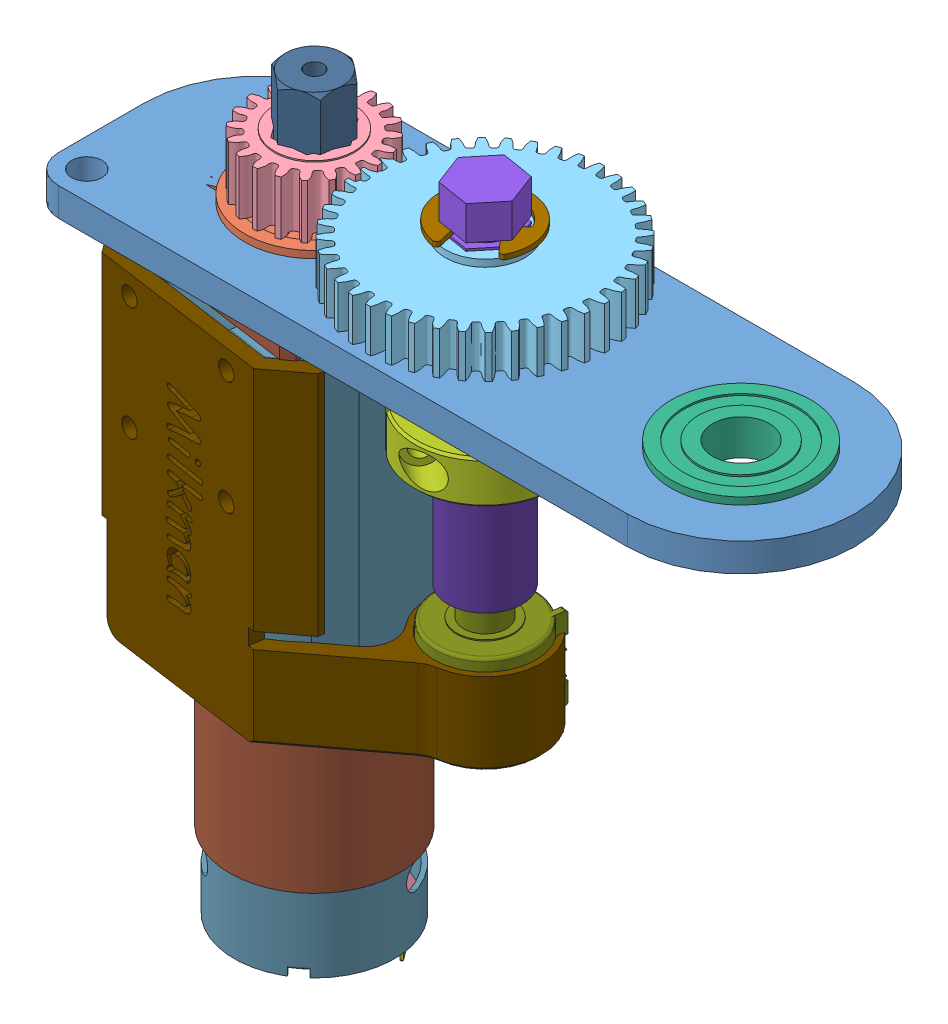
SolidWorks assembly 2018-311-A, configuration Default. Lengths in mm.
Overall size (159.56 178.63 76.64).
108 component instances, 61 part files, 41 mates.
Components (placement in the parent):
- 2018-311-D001-1: 2018-311-D001 [Default] at origin size (158.75 6.35 50.8)
- 2018-311-D003-1: 2018-311-D003 [Default] x (-0.99522 0 0.097661) z (-0.097661 0 -0.99522) size (31.12 7.94 31.12)
- 2018-311-D003-2: 2018-311-D003 [Default] at (38.1 0 0) x (-0.633642 0 0.773626) z (-0.773626 0 -0.633642) size (31.12 7.94 31.12)
- 72t_Aluminum_Spur_Gear_20_DP_1_2_Hex_Bore_VersaKeys_217-2716-1: 72t_Aluminum_Spur_Gear_20_DP_1_2_Hex_Bore_VersaKeys_217-2716 [Default] at (-78.0982 127.7889 163.8783) x (-0.237785 0 -0.971318) z (0 1 0) size (94.86 94.86 12.65) (hidden)
- VersaPlanetary-100-1-BAG-1: VersaPlanetary-100-1-BAG [Default] at (0 -16.625 -22.225) x (0 1 0) z (1 0 0) size (176.1 63.56 63.56) (hidden, flexible)
  - 217-2625-026 Rev1-1: 217-2625-026 Rev1 [Default] at (-6.5 22.225 0) x (0 -1 0) z (-1 0 0) size (44.45 42 18.13)
  - 217-2742-001 Rev4-1: 217-2742-001 Rev4 [Default] at (0.2002 22.225 0) x (1 0 0) z (0 -0.092627 0.995701) size (7 28 28)
  - 217-2742-001 Rev4-2: 217-2742-001 Rev4 [Default] at (8.2002 22.225 0) size (7 28 28)
  - 217-2625-017 Rev1_9714K61-1: 217-2625-017 Rev1_9714K61 [Default] at (7.42 22.3002 -0.342) x (0 0.56703 0.823697) z (0 -0.823697 0.56703) size (28.51 4.98 30.18)
  - 217-2625-003 Rev1-1: 217-2625-003 Rev1 [Default] at (7.4478 22.225 0) x (0 -0.99522 -0.097661) z (1 0 0) size (17 17 64.12)
  - 217-2625-018 Rev1_98541A410-1: 217-2625-018 Rev1_98541A410 [Default] at (-0.7046 22.225 0) x (1 0 0) z (0 -0.017452 0.999848) size (1 19.6 17.4)
  - 832-2250-Base-Kit-Screw_SSA0832-0500ZC-1: 832-2250-Base-Kit-Screw_SSA0832-0500ZC [Default] at (-43.4 4.725 -17.5) x (0 -0.767799 -0.640691) z (0 0.640691 -0.767799) size (6.73 61.21 6.73)
  - 832-2250-Base-Kit-Screw_SSA0832-0500ZC-2: 832-2250-Base-Kit-Screw_SSA0832-0500ZC [Default] at (-43.4 39.725 17.5) x (0 0.961307 0.275478) z (0 -0.275478 0.961307) size (6.73 61.21 6.73)
  - 217-2625-025 Rev1-1: 217-2625-025 Rev1 [Default] at (-35.9 22.225 0) x (0 -1 0) z (-1 0 0) size (44.45 42 18)
  - 217-4649-002 Rev1_SSA0832-0500ZC-1: 217-4649-002 Rev1_SSA0832-0500ZC [Default] at (-46.4 4.2645 17.9605) x (0 0.33842 -0.940995) z (0 0.940995 0.33842) size (6.73 16.76 6.73)
  - 217-4649-002 Rev1_SSA0832-0500ZC-2: 217-4649-002 Rev1_SSA0832-0500ZC [Default] at (-46.4 40.1855 -17.9605) x (0 -0.308932 -0.951084) z (0 0.951084 -0.308932) size (6.73 16.76 6.73)
  - 217-4649-006 Rev1_SSA0004-008BA-1: 217-4649-006 Rev1_SSA0004-008BA [Default] at (-43.4 22.225 12.5) x (0 0.5 -0.866025) z (0 -0.866025 -0.5) size (7 14 7)
  - 217-4649-006 Rev1_SSA0004-008BA-2: 217-4649-006 Rev1_SSA0004-008BA [Default] at (-43.4 22.225 -12.5) x (0 -0.5 0.866025) z (0 0.866025 0.5) size (7 14 7)
  - 217-2822-003 Rev4-1: 217-2822-003 Rev4 [Default] at (-44.9 22.225 0) x (0 -1 0) z (-1 0 0) size (42 42 4.8)
  - 217-3351 Rev2-1: 217-3351 Rev2 [Default] at (-46.4 22.225 0) x (0 0 1) z (1 0 0) size (59.11 59.11 84.5)
  - 217-2820 Rev1_Public-1: 217-2820 Rev1_Public [Default] at (-4.6546 22.225 0) x (0 -0.456494 0.889726) z (-1 0 0) size (39.26 38.9 17.4)
    - 217-2625-100-1: 217-2625-100 [Default] at origin size (39.26 38.9 12.7)
      - 217-2625-008 Rev1-1: 217-2625-008 Rev1 [Default] at origin size (34.7 34.7 4.7)
      - 217-2625-010 Rev1-1: 217-2625-010 Rev1 [Default] at (0 10.193 3.65) x (0.999813 0.019336 0) z (0 0 1) size (4 4 12)
      - 217-2625-010 Rev1-2: 217-2625-010 Rev1 [Default] at (8.691 -5.3258 3.65) size (4 4 12)
      - 217-2625-010 Rev1-3: 217-2625-010 Rev1 [Default] at (-8.691 -5.3258 3.65) size (4 4 12)
      - 217-2625-005 Rev1_Planet_Revolving_Follower01-1: 217-2625-005 Rev1_Planet_Revolving_Follower01 [Default] at (8.691 -5.3258 6.35) x (0.932816 0.360354 0) z (0 0 1) size (16.91 16.92 8)
      - 217-2625-005 Rev1_Planet_Revolving_Follower01-2: 217-2625-005 Rev1_Planet_Revolving_Follower01 [Default] at (-8.691 -5.3258 6.35) x (-0.932788 -0.360426 0) z (0 0 1) size (16.91 16.92 8)
      - 217-2625-005 Rev1_Planet_Revolving_Follower01-3: 217-2625-005 Rev1_Planet_Revolving_Follower01 [Default] at (0 10.193 6.35) x (0.893583 0.448898 0) z (0 0 1) size (16.91 16.92 8)
    - 217-2625-007 Rev1_Public-1: 217-2625-007 Rev1_Public [Default] at (0 0 6.7) x (0.992772 0.120019 0) z (0 0 1) size (14.49 14.49 12.72)
  - 217-2816-001 Rev1-1: 217-2816-001 Rev1 [Default] at (-6.35 22.225 0) x (0 -1 0) z (1 0 0) size (42 42 14.5)
  - 217-2820 Rev1_Public-2: 217-2820 Rev1_Public [Default] at (-17.15 22.225 0) x (0 0.184082 0.982911) z (-1 0 0) size (39.26 38.9 17.4)
    - 217-2625-100-1: 217-2625-100 [Default] at origin size (39.26 38.9 12.7)
      - 217-2625-008 Rev1-1: 217-2625-008 Rev1 [Default] at origin size (34.7 34.7 4.7)
      - 217-2625-010 Rev1-1: 217-2625-010 Rev1 [Default] at (0 10.193 3.65) x (0.999813 0.019336 0) z (0 0 1) size (4 4 12)
      - 217-2625-010 Rev1-2: 217-2625-010 Rev1 [Default] at (8.691 -5.3258 3.65) size (4 4 12)
      - 217-2625-010 Rev1-3: 217-2625-010 Rev1 [Default] at (-8.691 -5.3258 3.65) size (4 4 12)
      - 217-2625-005 Rev1_Planet_Revolving_Follower01-1: 217-2625-005 Rev1_Planet_Revolving_Follower01 [Default] at (8.691 -5.3258 6.35) x (0.932816 0.360354 0) z (0 0 1) size (16.91 16.92 8)
      - 217-2625-005 Rev1_Planet_Revolving_Follower01-2: 217-2625-005 Rev1_Planet_Revolving_Follower01 [Default] at (-8.691 -5.3258 6.35) x (-0.932788 -0.360426 0) z (0 0 1) size (16.91 16.92 8)
      - 217-2625-005 Rev1_Planet_Revolving_Follower01-3: 217-2625-005 Rev1_Planet_Revolving_Follower01 [Default] at (0 10.193 6.35) x (0.893583 0.448898 0) z (0 0 1) size (16.91 16.92 8)
    - 217-2625-007 Rev1_Public-1: 217-2625-007 Rev1_Public [Default] at (0 0 6.7) x (0.992772 0.120019 0) z (0 0 1) size (14.49 14.49 12.72)
  - 217-2816-001 Rev1-2: 217-2816-001 Rev1 [Default] at (-19.05 22.225 0) x (0 -1 0) z (1 0 0) size (42 42 14.5)
  - 217-4649-001 Rev1-1: 217-4649-001 Rev1 [Default] at (-32.746 22.225 0) x (0 -1 0) z (1 0 0) size (18 18 13)
  - 217-4649-007 Rev1_94105A824-1: 217-4649-007 Rev1_94105A824 [Default] at (-38.221 22.225 -6.7835) x (-0.996104 -0.088191 0) z (0 0 -1) size (4.83 4.83 4.9)
  - 217-2625-011 Rev1-1: 217-2625-011 Rev1 [Default] at (-37.4818 22.225 0) x (0 0 1) z (0 -1 0) size (8.01 7.5 7.94)
- 18t_Aluminum_Spur_Gear_20_DP_1_2_Hex_Bore_217-3209-1: 18t_Aluminum_Spur_Gear_20_DP_1_2_Hex_Bore_217-3209 [Default] at (-110.9542 132.5603 97.1007) x (0.641705 0 0.766952) z (0 1 0) size (25.77 25.98 12.65) (hidden)
- 18t_Aluminum_Spur_Gear_20_DP_1_2_Hex_Bore_217-3209-2: 18t_Aluminum_Spur_Gear_20_DP_1_2_Hex_Bore_217-3209 [Default] at (-182.575 146.5292 104.6947) size (25.77 25.98 12.65) (hidden)
- 20t_Aluminum_Spur_Gear_20_DP_1_2_Hex_Bore_217-2702-1: 20t_Aluminum_Spur_Gear_20_DP_1_2_Hex_Bore_217-2702 [Default] at (-137.1638 137.7932 146.6933) size (28.2 28.2 12.65) (hidden)
- 22t_Aluminum_Spur_Gear_20_DP_1_2_Hex_Bore_217-5462-1: 22t_Aluminum_Spur_Gear_20_DP_1_2_Hex_Bore_217-5462 [Default] at (-93.6554 135.0876 115.8384) size (30.62 30.78 12.6) (hidden)
- 24t_Aluminum_Spur_Gear_20_DP_1_2_Hex_Bore_217-2704-1: 24t_Aluminum_Spur_Gear_20_DP_1_2_Hex_Bore_217-2704 [Default] at (-142.8434 137.5346 78.9599) size (33.29 33.29 12.65) (hidden)
- 26t_Aluminum_Spur_Gear_20_DP_1_2_Hex_Bore_217-5465-1: 26t_Aluminum_Spur_Gear_20_DP_1_2_Hex_Bore_217-5465 [Default] at (-164.0269 145.3211 90.8877) size (36.01 36.14 12.6) (hidden)
- 36t_Aluminum_Spur_Gear_20_DP_1_2_Hex_Bore_217-3214-1: 36t_Aluminum_Spur_Gear_20_DP_1_2_Hex_Bore_217-3214 [Default] at (-132.0482 136.4308 133.3593) x (0.959958 0 0.280144) z (0 1 0) size (48.63 48.63 12.65) (hidden)
- 18t_Aluminum_Spur_Gear_20_DP_1_2_Hex_Bore_217-3209-3: 18t_Aluminum_Spur_Gear_20_DP_1_2_Hex_Bore_217-3209 [Default] at (38.1 -6.3246 0) x (-0.935563 0 0.353159) z (0 1 0) size (25.77 25.98 12.65)
- 20t_Aluminum_Spur_Gear_20_DP_1_2_Hex_Bore_217-27021-1: 20t_Aluminum_Spur_Gear_20_DP_1_2_Hex_Bore_217-27021 [Default] at (0 14.2621 0) x (0.910716 0 0.413033) z (0 1 0) size (28.2 28.2 12.65)
- 40t_Aluminum_Spur_Gear_20_DP_1_2_Hex_Bore_217-2708-1: 40t_Aluminum_Spur_Gear_20_DP_1_2_Hex_Bore_217-2708 [Default] at (38.1 14.2621 0) x (0.773626 0 0.633642) z (0 1 0) size (53.62 53.62 12.65)
- 0_500_ID_x_1_125_OD_x_0_313_WD_Flanged_Bearing_217-2731-1: 0_500_ID_x_1_125_OD_x_0_313_WD_Flanged_Bearing_217-2731 [Default] at (95.25 0 0) x (0.821808 0 -0.569765) z (0.569765 0 0.821808) size (31.12 7.94 31.12)
- 2018-308-D005-1: 2018-308-D005 [Default] at (38.1 -22.6219 0) x (-0.633642 0 0.773626) z (-0.773626 0 -0.633642) size (31.47 9.53 31.5)
- 2018-311-D004-1: 2018-311-D004 [Default] at (38.1 3.5719 0) x (0.935563 0 -0.353159) z (0 -1 0) size (12.7 14.66 52.39)
- 98408A138_SIDE-MOUNT EXTERNAL RETAINING RING  E-STYLE-1: 98408A138_SIDE-MOUNT EXTERNAL RETAINING RING  E-STYLE [98408A138] at (38.1 21.5678 0) x (0 1 0) z (0.451388 0 0.892328) size (1.07 20.32 18.5)
- 2018-321-A-1: 2018-321-A [Default] at (-27.1528 -37.1991 -28.8748) x (-0.139173 0 0.990268) z (0 1 0) size (53.25 53.25 170.06)
  - am-3758+-+100_1+-+57+Sport Banebots-1: am-3758+-+100_1+-+57+Sport Banebots [Default] at origin size (48.57 48.57 106.05)
    - am-XXXX - 57 Sport 500 Hex Output Plug-1: am-XXXX - 57 Sport 500 Hex Output Plug [Default] at (24.8149 30.9071 37.1991) size (44.45 44.45 56.9)
      - am-XXXX - 57 Sport 500 Hex Shaft-1: am-XXXX - 57 Sport 500 Hex Shaft [Default] at (0 0 6.2738) x (0.999982 0.006056 0) z (0 0 1) size (16.1 12.67 56.9)
      - Output Block-1: Output Block [Default] at origin size (44.45 44.45 20.32)
      - FR8ZZ Bearing-1: FR8ZZ Bearing [Default] at (8.9053 -5.9773 -13.8938) x (0.999973 0.007281 0) z (0 0 1) size (31.75 31.75 7.95)
      - FR8ZZ Bearing-2: FR8ZZ Bearing [Default] at (5.8713 8.9755 6.2738) x (0.923728 0.383049 0) z (0 0 -1) size (31.75 31.75 7.95)
      - retaining Ring 0500 - Mcm 98410A122_98410A122-1: retaining Ring 0500 - Mcm 98410A122_98410A122 [Default] at (0 0 -14.3891) x (0 0 1) z (-0.999848 0.017452 0) size (0.89 16.1 14.34)
    - am-XXXX - 57 Sport 3 Stage Ring Gear Housing-1: am-XXXX - 57 Sport 3 Stage Ring Gear Housing [Default] at (24.8149 30.9071 2.4011) size (47.68 47.68 63.27)
    - Thrust washer - 775 Sport-1: Thrust washer - 775 Sport [Default] at (24.8149 30.9071 -27.7241) x (0.992053 0.125818 0) z (0 0 1) size (31 31 1.52)
    - am-3765 - 57 Sport Motor Block-1: am-3765 - 57 Sport Motor Block [Default] at (24.8149 30.9071 -33.0319) x (0 1 0) z (0 0 1) size (45.76 47.07 8.89)
    - 10-32 X 375 SHCS_90128A940-1: 10-32 X 375 SHCS_90128A940 [Default] at (42.7754 48.8676 27.6741) x (-0.100111 -0.994976 0) z (0 0 -1) size (7.92 7.92 14.58)
    - 10-32 X 375 SHCS_90128A940-2: 10-32 X 375 SHCS_90128A940 [Default] at (6.8543 12.9466 27.6741) x (0.058911 -0.998263 0) z (0 0 -1) size (7.92 7.92 14.58)
    - 5_1 HD Output Stage-1: 5_1 HD Output Stage [Default] at (-68.9808 196.0711 114.0764) x (-0.524 0.851718 0) z (0 0 -1) size (39.35 39.35 20.95)
      - 5_1 HD Output Stage Carrier Plate-1: 5_1 HD Output Stage Carrier Plate [Default] at (-189.8221 -6.6586 94.2255) size (30.99 30.99 20.93)
      - 18T Long Planet Gear-1: 18T Long Planet Gear [Default] at (-200.8282 -6.6808 106.2401) x (0 0 1) z (0.923728 0.383049 0) size (13.43 13.84 14)
      - 18T Long Planet Gear-2: 18T Long Planet Gear [Default] at (-189.8444 4.3475 106.2401) x (0 0 1) z (0.383049 -0.923728 0) size (13.43 13.84 14)
      - 18T Long Planet Gear-3: 18T Long Planet Gear [Default] at (-178.816 -6.6363 106.2401) x (0 0 1) z (-0.923728 -0.383049 0) size (13.43 13.84 14)
      - 18T Long Planet Gear-4: 18T Long Planet Gear [Default] at (-189.7998 -17.6647 106.2401) x (0 0 1) z (-0.383049 0.923728 0) size (13.43 13.84 14)
    - am-XXXX - 5_1 Sun Gear 4_1 Carrier Plate-1: am-XXXX - 5_1 Sun Gear 4_1 Carrier Plate [Default] at (24.8149 30.9071 -13.6055) x (-0.898594 -0.43878 0) z (0 0 -1) size (40.05 39.58 20.09)
      - 5_1 Sun Gear 57 Sport Stage Carrier Plate-1: 5_1 Sun Gear 57 Sport Stage Carrier Plate [Default] at origin size (31.12 31.12 12.6)
      - 12T Sun Gear-1: 12T Sun Gear [Default] at (3.5865 0.6306 4.6787) x (0 0 1) z (-0.923728 -0.383049 0) size (12.75 9.53 9.53)
      - 16T Planet Gear-1: 16T Planet Gear [Default] at (0.9198 10.3381 9.8136) x (0 0 -1) z (-0.923728 -0.383049 0) size (7.09 12.42 12.42)
      - 16T Planet Gear-2: 16T Planet Gear [Default] at (12.4377 -0.8696 9.8136) x (0 0 -1) z (-0.85131 -0.524663 0) size (7.09 12.42 12.42)
      - 16T Planet Gear-3: 16T Planet Gear [Default] at (1.1732 -12.0926 9.8136) x (0 0 -1) z (-0.777574 -0.628792 0) size (7.09 12.42 12.42)
      - 16T Planet Gear-4: 16T Planet Gear [Default] at (-10.1307 -0.6136 9.8136) x (0 0 -1) z (-0.715577 -0.698533 0) size (7.09 12.42 12.42)
    - am-XXXX - 5_1 Stage-1: am-XXXX - 5_1 Stage [Default] at (24.8149 30.9071 -1.0975) x (-0.884358 0.46681 0) z (0 0 -1) size (37.89 36.82 20.09)
      - 5_1 Stage Carrier Plate-1: 5_1 Stage Carrier Plate [Default] at origin size (31.12 31.12 12.6)
      - 18T Short Planet Gear-1: 18T Short Planet Gear [Default] at (-0.9034 11.1608 11.3032) x (0 0 -1) z (0.019286 0.999814 0) size (7 13.84 14)
      - 18T Short Planet Gear-2: 18T Short Planet Gear [Default] at (9.5654 0.4561 11.3032) x (0 0 -1) z (-0.139481 0.990225 0) size (7 13.84 14)
      - 18T Short Planet Gear-3: 18T Short Planet Gear [Default] at (-1.0383 -10.2271 11.3032) x (0 0 -1) z (-0.264433 0.964404 0) size (7 13.84 14)
      - 18T Short Planet Gear-4: 18T Short Planet Gear [Default] at (-11.6179 0.2284 11.3032) x (0 0 -1) z (-0.353176 0.935557 0) size (7 13.84 14)
      - 12T Sun Gear-1: 12T Sun Gear [Default] at (-3.5865 -0.6306 4.6787) x (0 0 1) z (0.923728 0.383049 0) size (12.75 9.53 9.53)
    - 10-32 X 375 SHCS_90128A940-3: 10-32 X 375 SHCS_90128A940 [Default] at (42.7754 12.9466 27.6741) x (0.058911 -0.998263 0) z (0 0 -1) size (7.92 7.92 14.58)
  - CCL-9015-am-0912-1: CCL-9015-am-0912 [Default] at (22.8966 30.5762 -61.5239) x (0 0 -1) z (-0.707107 -0.707107 0) size (82.02 37.83 37.47)
    - AM-0912 terminal-1: AM-0912 terminal [Default] at (29.27 -13.055 -1.5854) size (10.06 0.6 3.8)
    - AM-0912 output bushing-1: AM-0912 output bushing [Default] at (-28.166 1.123 -1.5904) size (4.5 10.97 10.97)
    - AM-0912 end cap-1: AM-0912 end cap [Default] at (24.952 1.123 -1.5904) size (6.48 34.65 34.46)
    - AM-0912 cap bushing-1: AM-0912 cap bushing [Default] at (31.302 1.123 -1.5904) size (3.04 8.08 8.08)
    - AM-0912 shield-1: AM-0912 shield [Default] at (-21.634 1.123 -1.5904) x (1 0 0) z (0 -1 0) size (36.88 37.47 37.83)
    - AM-0912 shaft-1: AM-0912 shaft [Default] at (-32.682 1.123 -1.5904) x (1 0 0) z (0 0.970706 0.240271) size (80.92 3.29 3.26)
    - AM-0912 terminal housing-1: AM-0912 terminal housing [Default] at (30.286 -13.101 -1.5904) x (-1 0 0) z (0 0 1) size (4.06 4.83 19.05)
    - AM-0912 terminal housing-2: AM-0912 terminal housing [Default] at (30.286 15.347 -1.5904) x (-1 0 0) z (0 0 -1) size (4.06 4.83 19.05)
    - AM-0912 terminal-2: AM-0912 terminal [Default] at (29.27 15.301 -1.5954) size (10.06 0.6 3.8)
    - AM-0912 housing-1: AM-0912 housing [Default] at (32.318 1.123 -1.5904) size (61.5 35.8 35.8)
- 2018-311-D005-1: 2018-311-D005 [Default] at (38.1 -28.3877 0) x (0 1 0) z (-0.488915 0 -0.872331) size (11.53 6.17 6.17)
- 2018-311-D006-1: 2018-311-D006 [Default] at (38.1 -55.0323 0) x (-0.990268 0 -0.139173) z (0 -1 0) size (22.23 26.23 39.28)
- 2018-311-D007-1: 2018-311-D007 [Default] at (38.1 -35.4489 0) x (0 -1 0) z (-0.846714 0 0.532048) size (25.65 16.54 16.54)
- 2018-311-D010-1: 2018-311-D010 [Default] at (19.3108 -28.575 -137.4032) x (0.139173 0 -0.990268) z (0 1 0) size (45.63 77.48 72.74)
Mates (geometry in assembly coordinates):
- Concentric1: concentric aligned: cylinder of 2018-311-D003-1 through (0 0 0) axis (0 1 0) radius 14.2748; cylinder of 2018-311-D001-1 through (0 0 0) axis (0 1 0) radius 14.2875
- Coincident1: coincident anti-aligned: plane of 2018-311-D001-1 through (95.25 6.35 0) normal (0 1 0); plane of 2018-311-D003-1 through (-15.4831 6.35 1.5194) normal (0 -1 0)
- Concentric2: concentric aligned: cylinder of 2018-311-D003-1 through (0 6.35 0) axis (0 1 0) radius 15.5575; cylinder of VersaPlanetary-100-1-BAG-1/217-2625-003 Rev1-1 through (0 -1.4248 0) axis (0 1 0) radius 8.5
- Parallel1: parallel anti-aligned: plane of 2018-311-D003-1 through (4.2755 7.9375 5.971) normal (-0.097661 0 -0.99522); plane of VersaPlanetary-100-1-BAG-1/217-2625-003 Rev1-1 through (-3.0285 40.5752 6.6777) normal (0.097661 0 0.99522)
- Coincident4: coincident anti-aligned: plane of 2018-311-D001-1 through (95.25 6.35 0) normal (0 1 0); plane of 2018-311-D003-2 through (28.2421 6.35 12.0357) normal (0 -1 0)
- Concentric3: concentric aligned: cylinder of 2018-311-D001-1 through (38.1 0 0) axis (0 1 0) radius 14.2875; cylinder of 2018-311-D003-2 through (38.1 0 0) axis (0 1 0) radius 14.2748
- Coincident8: coincident anti-aligned: plane of 2018-311-D001-1 through (95.25 0 0) normal (0 -1 0); plane of VersaPlanetary-100-1-BAG-1/217-2625-026 Rev1-1 through (22.225 0 22.225) normal (0 1 0)
- Concentric7: concentric anti-aligned: cylinder of 2018-311-D003-2 through (38.1 6.35 0) axis (0 1 0) radius 15.5575; cylinder of 18t_Aluminum_Spur_Gear_20_DP_1_2_Hex_Bore_217-3209-3 through (38.1 0 0) axis (0 -1 0) radius 8.89
- Parallel5: parallel aligned: plane of 2018-311-D003-2 through (30.853 7.9375 -1.1893) normal (0.773626 0 0.633642); plane of 18t_Aluminum_Spur_Gear_20_DP_1_2_Hex_Bore_217-3209-3 through (35.495 -12.6492 -6.901) normal (0.773626 0 0.633642)
- Coincident12: coincident anti-aligned: plane of 2018-311-D003-2 through (38.1 0 0) normal (0 -1 0); plane of 18t_Aluminum_Spur_Gear_20_DP_1_2_Hex_Bore_217-3209-3 through (38.1 0 0) normal (0 1 0)
- Concentric9: concentric anti-aligned: cylinder of 2018-311-D003-2 through (38.1 7.9375 0) axis (0 1 0) radius 12.7; cylinder of 40t_Aluminum_Spur_Gear_20_DP_1_2_Hex_Bore_217-2708-1 through (38.1 20.5867 0) axis (0 -1 0) radius 8.89
- Parallel7: parallel aligned: plane of 2018-311-D003-2 through (40.6936 7.9375 6.8707) normal (0.161937 0 -0.986801); plane of 40t_Aluminum_Spur_Gear_20_DP_1_2_Hex_Bore_217-2708-1 through (40.705 20.5867 6.901) normal (0.161937 0 -0.986801)
- Coincident16: coincident anti-aligned: plane of 2018-311-D003-2 through (38.1 7.9375 0) normal (0 1 0); plane of 40t_Aluminum_Spur_Gear_20_DP_1_2_Hex_Bore_217-2708-1 through (38.1 7.9375 0) normal (0 -1 0)
- Concentric10: concentric anti-aligned: cylinder of 2018-311-D003-1 through (0 7.9375 0) axis (0 1 0) radius 12.7; cylinder of 20t_Aluminum_Spur_Gear_20_DP_1_2_Hex_Bore_217-27021-1 through (0 20.5867 0) axis (0 -1 0) radius 8.89
- Parallel8: parallel anti-aligned: plane of VersaPlanetary-100-1-BAG-1/217-2625-003 Rev1-1 through (7.2973 40.5752 -0.7161) normal (0.813055 0 -0.582187); plane of 20t_Aluminum_Spur_Gear_20_DP_1_2_Hex_Bore_217-27021-1 through (3.0467 20.5867 -6.7178) normal (-0.813055 0 0.582187)
- Coincident18: coincident anti-aligned: plane of 2018-311-D003-1 through (0 7.9375 0) normal (0 1 0); plane of 20t_Aluminum_Spur_Gear_20_DP_1_2_Hex_Bore_217-27021-1 through (0 7.9375 0) normal (0 -1 0)
- Concentric12: concentric aligned: cylinder of 2018-311-D001-1 through (95.25 0 0) axis (0 1 0) radius 14.2875; cylinder of 0_500_ID_x_1_125_OD_x_0_313_WD_Flanged_Bearing_217-2731-1 through (95.25 0 0) axis (0 1 0) radius 14.2875
- Coincident20: coincident anti-aligned: plane of 2018-311-D001-1 through (95.25 6.35 0) normal (0 1 0); plane of 0_500_ID_x_1_125_OD_x_0_313_WD_Flanged_Bearing_217-2731-1 through (108.0353 6.35 -8.8641) normal (0 -1 0)
- Parallel9: parallel aligned: plane of 2018-311-D001-1 through (-38.1 6.35 -25.4) normal (0 0 -1); plane of VersaPlanetary-100-1-BAG-1/217-2625-026 Rev1-1 through (-8.7 -18.125 -21) normal (0 0 -1)
- Concentric13: concentric aligned: cylinder of 18t_Aluminum_Spur_Gear_20_DP_1_2_Hex_Bore_217-3209-3 through (38.1 0 0) axis (0 -1 0) radius 8.89; cylinder of 2018-308-D005-1 through (38.1 -13.0969 0) axis (0 -1 0) radius 15.748
- Parallel10: parallel aligned: plane of 18t_Aluminum_Spur_Gear_20_DP_1_2_Hex_Bore_217-3209-3 through (40.705 -12.6492 6.901) normal (-0.773626 0 -0.633642); plane of 2018-308-D005-1 through (40.6895 -22.6219 6.8599) normal (-0.773626 0 -0.633642)
- Coincident23: coincident aligned: plane of 2018-308-D005-1 through (38.1 -22.6219 0) normal (0 -1 0); plane of 2018-311-D004-1 through (38.1 -22.6219 0) normal (0 -1 0)
- Concentric14: concentric anti-aligned: cylinder of 2018-311-D003-2 through (38.1 6.35 0) axis (0 1 0) radius 15.5575; cylinder of 2018-311-D004-1 through (38.1 -22.6219 0) axis (0 -1 0) radius 2.5527
- Coincident24: coincident anti-aligned: plane of 2018-308-D005-1 through (40.6895 -22.6219 6.8599) normal (-0.773626 0 -0.633642); plane of 2018-311-D004-1 through (45.3356 -22.6219 1.1874) normal (0.773626 0 0.633642)
- Concentric15: concentric anti-aligned: cylinder of 2018-311-D004-1 through (38.1 29.7656 0) axis (0 1 0) radius 5.0292; cylinder of 98408A138_SIDE-MOUNT EXTERNAL RETAINING RING  E-STYLE-1 through (38.1 22.1012 0) axis (0 -1 0) radius 4.9784
- Coincident25: coincident anti-aligned: plane of 2018-311-D004-1 through (41.5865 21.0344 9.2362) normal (0 1 0); plane of 98408A138_SIDE-MOUNT EXTERNAL RETAINING RING  E-STYLE-1 through (38.1 21.0344 0) normal (0 -1 0)
- Width1: width anti-aligned: plane of 40t_Aluminum_Spur_Gear_20_DP_1_2_Hex_Bore_217-2708-1 through (38.1 20.5867 0) normal (0 1 0); plane of 18t_Aluminum_Spur_Gear_20_DP_1_2_Hex_Bore_217-3209-3 through (38.1 -12.6492 0) normal (0 -1 0); plane of 98408A138_SIDE-MOUNT EXTERNAL RETAINING RING  E-STYLE-1 through (38.1 21.0344 0) normal (0 -1 0); plane of 2018-308-D005-1 through (28.1214 -13.0969 12.1831) normal (0 1 0)
- Parallel11: parallel aligned: plane of 2018-311-D001-1 through (95.25 6.35 0) normal (0 1 0); plane of 2018-321-A-1/am-3758+-+100_1+-+57+Sport Banebots-1/am-XXXX - 57 Sport 500 Hex Output Plug-1/Output Block-1 through (0 0 0) normal (0 1 0)
- Concentric16: concentric anti-aligned: cylinder of 2018-311-D001-1 through (0 0 0) axis (0 1 0) radius 14.2875; cylinder of 2018-321-A-1/am-3758+-+100_1+-+57+Sport Banebots-1/am-XXXX - 57 Sport 500 Hex Output Plug-1/Output Block-1 through (0 6.35 0) axis (0 -1 0) radius 19.05
- Angle1: planar angle = 0.139626 rad aligned: plane of 2018-321-A-1/am-3758+-+100_1+-+57+Sport Banebots-1/am-XXXX - 57 Sport 3 Stage Ring Gear Housing-1 through (-26.8948 -3.175 20.2667) normal (-0.139173 0 0.990268); plane of 2018-311-D001-1 through (95.25 6.35 25.4) normal (0 0 1)
- Coincident26: coincident anti-aligned: plane of 2018-311-D001-1 through (95.25 0 0) normal (0 -1 0); plane of 2018-321-A-1/am-3758+-+100_1+-+57+Sport Banebots-1/am-XXXX - 57 Sport 500 Hex Output Plug-1/Output Block-1 through (0 0 0) normal (0 1 0)
- Concentric18: concentric aligned: cylinder of 2018-311-D004-1 through (38.1 -22.6219 0) axis (0 -1 0) radius 2.5527; cylinder of 2018-311-D005-1 through (38.1 -22.6219 0) axis (0 -1 0) radius 3.0861
- Coincident28: coincident anti-aligned: plane of 2018-311-D004-1 through (38.1 -22.6219 0) normal (0 -1 0); plane of 2018-311-D005-1 through (38.1 -22.6219 0) normal (0 1 0)
- Concentric19: concentric aligned: cylinder of 2018-311-D005-1 through (38.1 -22.6219 0) axis (0 -1 0) radius 3.0861; cylinder of 2018-311-D006-1 through (38.1 -34.1535 0) axis (0 -1 0) radius 3.175
- Concentric20: concentric anti-aligned: cylinder of 2018-311-D005-1 through (38.1 -22.6219 0) axis (0 -1 0) radius 3.0861; cylinder of 2018-311-D007-1 through (38.1 -48.2759 0) axis (0 1 0) radius 8.2677
- Coincident29: coincident anti-aligned: plane of 2018-308-D005-1 through (38.1 -22.6219 0) normal (0 -1 0); plane of 2018-311-D007-1 through (38.1 -22.6219 0) normal (0 1 0)
- Coincident30: coincident anti-aligned: plane of 2018-311-D005-1 through (38.1 -34.1535 0) normal (0 -1 0); plane of 2018-311-D006-1 through (38.1 -34.1535 0) normal (0 1 0)
- Coincident31: coincident anti-aligned: plane of 2018-321-A-1/am-3758+-+100_1+-+57+Sport Banebots-1/am-XXXX - 57 Sport 3 Stage Ring Gear Housing-1 through (-26.8948 -3.175 20.2667) normal (-0.139173 0 0.990268); plane of 2018-311-D010-1 through (-21.6993 -3.175 20.9969) normal (0.139173 0 -0.990268)
- Concentric21: concentric aligned: cylinder of 2018-321-A-1/am-3758+-+100_1+-+57+Sport Banebots-1/am-XXXX - 57 Sport 3 Stage Ring Gear Housing-1 through (-15.8905 -7.62 21.8133) axis (-0.139173 0 0.990268) radius 2.0193; cylinder of 2018-311-D010-1 through (-9.9822 -7.62 -20.2264) axis (-0.139173 0 0.990268) radius 2.0193
- Concentric22: concentric aligned: cylinder of 2018-321-A-1/am-3758+-+100_1+-+57+Sport Banebots-1/am-XXXX - 57 Sport 3 Stage Ring Gear Housing-1 through (9.2623 -33.02 25.3483) axis (-0.139173 0 0.990268) radius 2.0193; cylinder of 2018-311-D010-1 through (15.1706 -33.02 -16.6914) axis (-0.139173 0 0.990268) radius 2.0193
- Parallel12: parallel anti-aligned: plane of 2018-311-D006-1 through (-69542.4138 -68.6975 495134.8828) normal (0.990268 0 0.139173); plane of 2018-311-D010-1 through (46.844 -75.9104 -5.1835) normal (-0.990268 0 -0.139173)
